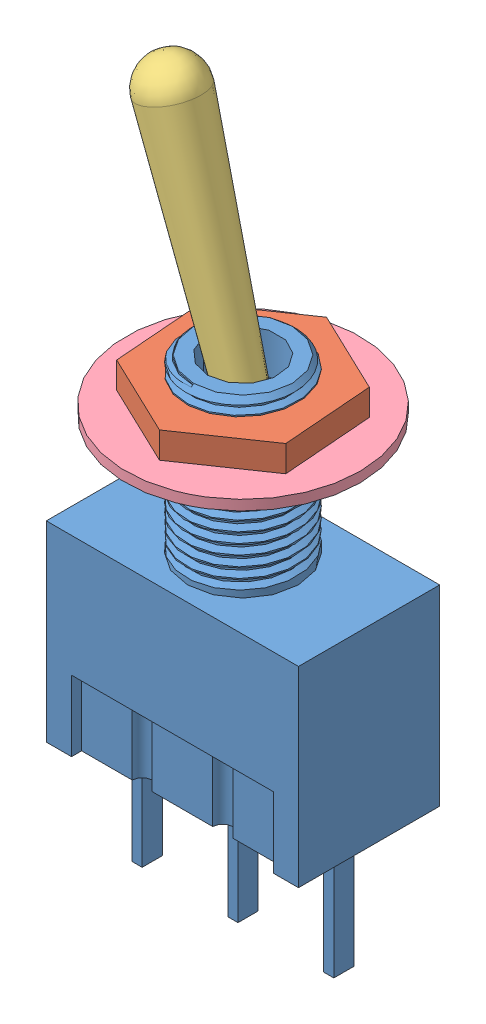
SolidWorks assembly toggle_mts1_assembly, configuration Default. Lengths in mm.
Overall size (15.55 36.55 15.55).
4 component instances, 4 part files, 7 mates.
Components (placement in the parent):
- toggle_mts_1_base_thread-1: toggle_mts_1_base_thread [Default] at origin size (12.5 25.17 7)
- toggle_mts_1_nut-1: toggle_mts_1_nut [Default] at (0 15.8967 -0.4087) x (-0.07757 0 -0.996987) z (0.996987 0 -0.07757) size (9.01 1.63 7.8)
- toggle_mts_1_lever-1: toggle_mts_1_lever [Default] at (0 16.1983 -0.4087) x (0 0 1) z (-0.956305 -0.292372 0) size (3 13.5 3)
- toggle_mts_1_washer-1: toggle_mts_1_washer [Default] at (0 15.3967 -0.4087) x (0.895652 0 -0.444756) z (0.444756 0 0.895652) size (11.6 0.5 11.6)
Mates (geometry in assembly coordinates):
- Screw1: screw = 0.5 aligned: line of toggle_mts_1_base_thread-1 through (0 17.7 -0.4087) axis (0 -1 0); line of toggle_mts_1_nut-1 through (0 17.1967 -0.4087) axis (0 -1 0)
- Coincident2: coincident anti-aligned: line of toggle_mts_1_base_thread-1 through (0 16.1983 0) axis (0 0 -1); line of toggle_mts_1_lever-1 through (0 16.1983 -1.4087) axis (0 0 1)
- Coincident3: coincident: line of toggle_mts_1_lever-1 through (-3.5085 27.6739 -0.4087) axis (0.292372 -0.956305 0)
- LimitAngle2: limit planar angle = 0.296706 rad aligned: line of toggle_mts_1_lever-1 through (-3.5085 27.6739 -0.4087) axis (0.292372 -0.956305 0); line of toggle_mts_1_base_thread-1 through (0 17.7 -0.4087) axis (0 -1 0)
- Concentric1: concentric aligned: cylinder of toggle_mts_1_base_thread-1 through (0 18 -0.4087) axis (0 -1 0) radius 2.75; cylinder of toggle_mts_1_washer-1 through (0 15.8967 -0.4087) axis (0 -1 0) radius 2.85
- Coincident6: coincident anti-aligned: plane of toggle_mts_1_nut-1 through (0 15.8967 -0.4087) normal (0 -1 0); plane of toggle_mts_1_washer-1 through (0 15.8967 -0.4087) normal (0 1 0)
- LimitDistance1: limit distance = 5.8967 mm anti-aligned: plane of toggle_mts_1_washer-1 through (0 15.3967 -0.4087) normal (0 -1 0); plane of toggle_mts_1_base_thread-1 through (0 9.5 0) normal (0 1 0)
